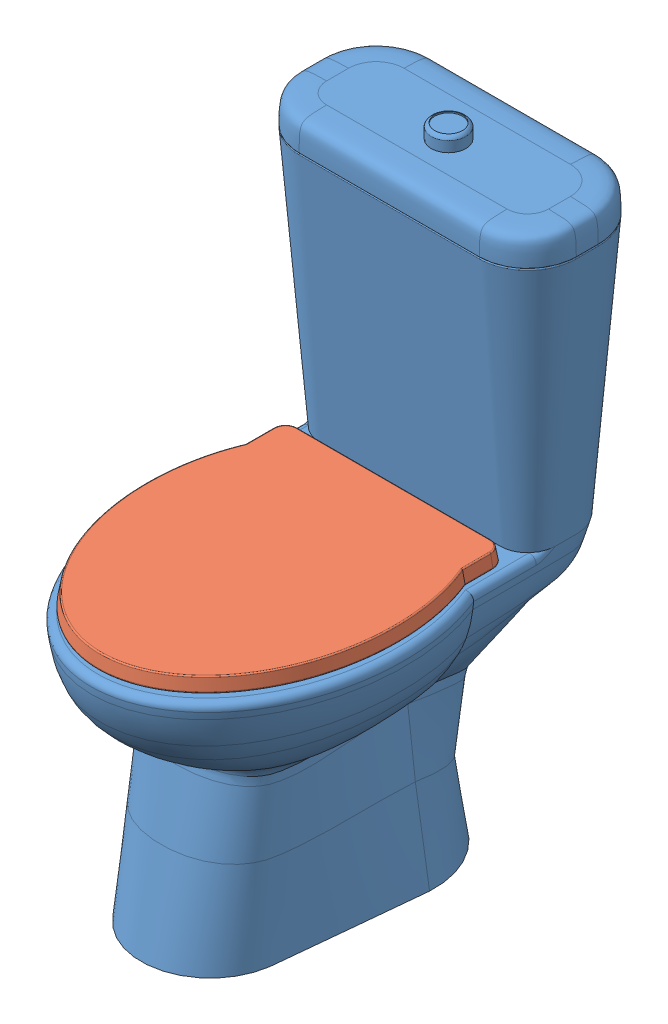
SolidWorks assembly toilette, configuration Défaut. Lengths in mm.
Overall size (410.24 826.06 618.55).
7 component instances, 7 part files, 5 mates.
Components (placement in the parent):
- chiote-1: chiote [Défaut] at origin size (410.24 826.06 611.93)
- Pièce1^toilette-1: Pièce1^toilette [Défaut] at origin (virtual)
- Pièce2^toilette-1: Pièce2^toilette [Défaut] at origin (virtual)
- Pièce3^toilette-1: Pièce3^toilette [Défaut] at origin (virtual)
- Pièce5^toilette-1: Pièce5^toilette [Défaut] at origin (virtual)
- Pièce6^toilette-1: Pièce6^toilette [Défaut] at origin (virtual)
- Pièce7^toilette-1: Pièce7^toilette [Défaut] at (0 395 0) x (1 0 0) z (0 1 0) size (398.82 446.61 29.06) (virtual)
Mates (geometry in assembly coordinates):
- Coïncidente5: coordinate: point of ?
- Sur place2: in place: plane of ? through (0 405 0) normal (0 1 0); moOrthogonalPlaneRef_w of ? through (0 405 0) normal (0 0 -1); line of ? through (-55 0 405) axis (0 1 0); unknown of Pièce7^toilette-1
- Coïncidente7: coincident aligned: plane of Pièce7^toilette-1; plane of assembly
- Coïncidente8: coincident aligned: plane of Pièce7^toilette-1 through (0 395 0) normal (0 0 -1); moOrthogonalPlaneRef_w of assembly
- Coïncidente9: coincident anti-aligned: plane of Pièce7^toilette-1; moOrthogonalPlaneRef_w of assembly
